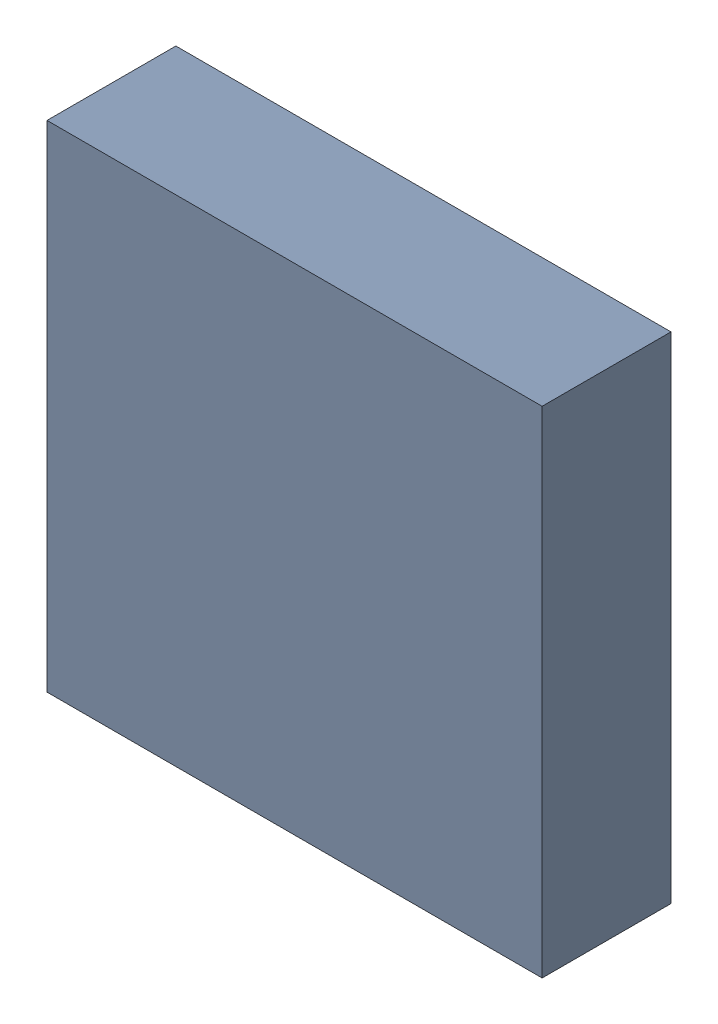
SolidWorks assembly U2, configuration Default. Lengths in mm.
Overall size (3.65 3.65 0.95).
2 component instances, 1 part files, 0 mates.
Components (placement in the parent):
- 870946080-1: 870946080 [Default] at (8.751 37.539 -2.6006) size (3.65 3.65 0.95)
  - Extruded_19-1: Extruded_19 [Default] at origin size (3.65 3.65 0.95)
